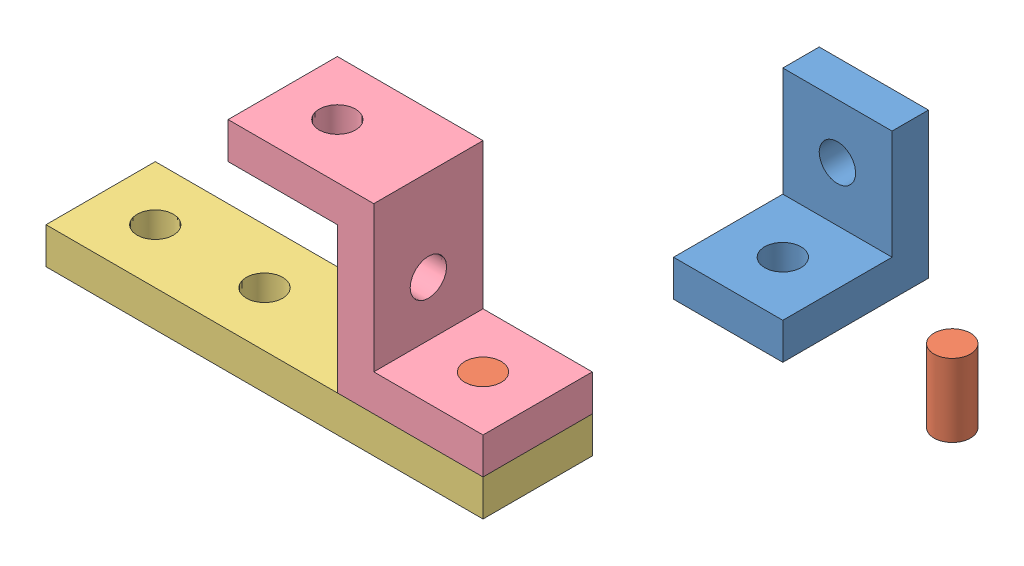
SolidWorks assembly Schoolwork - Module 2, configuration Default. Lengths in mm.
Overall size (155.93 71.76 109.03).
5 component instances, 4 part files, 5 mates.
Components (placement in the parent):
- L-bracket-1: L-bracket [Default] at (50.322 15.4066 -36.4446) size (30 40 40)
- Peg - Short-1: Peg - Short [Default] at (37.0343 16.0105 57.5846) size (10 20 10)
- Quad Plate-1: Quad Plate [Default] at (-7.9657 6.0105 57.5846) size (120 10 30)
- Z-bracket-1: Z-bracket [Default] at (12.0343 16.0105 57.5846) x (0 0 -1) z (1 0 0) size (30 50 70)
- Peg - Short-2: Peg - Short [Default] at (82.9595 4.2463 -25.3351) size (10 20 10)
Mates (geometry in assembly coordinates):
- Concentric1: concentric anti-aligned: cylinder of Peg - Short-1 through (37.0343 26.0105 57.5846) axis (0 -1 0) radius 5; cylinder of Quad Plate-1 through (37.0343 6.0105 57.5846) axis (0 1 0) radius 5
- Coincident1: coincident aligned: plane of Peg - Short-1 through (37.0343 6.0105 57.5846) normal (0 -1 0); plane of Quad Plate-1 through (-7.9657 6.0105 57.5846) normal (0 -1 0)
- Concentric3: concentric: cylinder of Peg - Short-1 through (37.0343 26.0105 57.5846) axis (0 -1 0) radius 5; cylinder of Z-bracket-1 through (37.0343 16.0105 57.5846) axis (0 1 0) radius 5
- Coincident4: coincident: plane of Quad Plate-1 through (-7.9657 16.0105 57.5846) normal (0 1 0); plane of Z-bracket-1 through (52.0343 16.0105 72.5846) normal (0 -1 0)
- Coincident5: coincident aligned: line of Quad Plate-1 through (52.0343 16.0105 42.5846) axis (-1 0 0); line of Z-bracket-1 through (52.0343 16.0105 42.5846) axis (-1 0 0)
